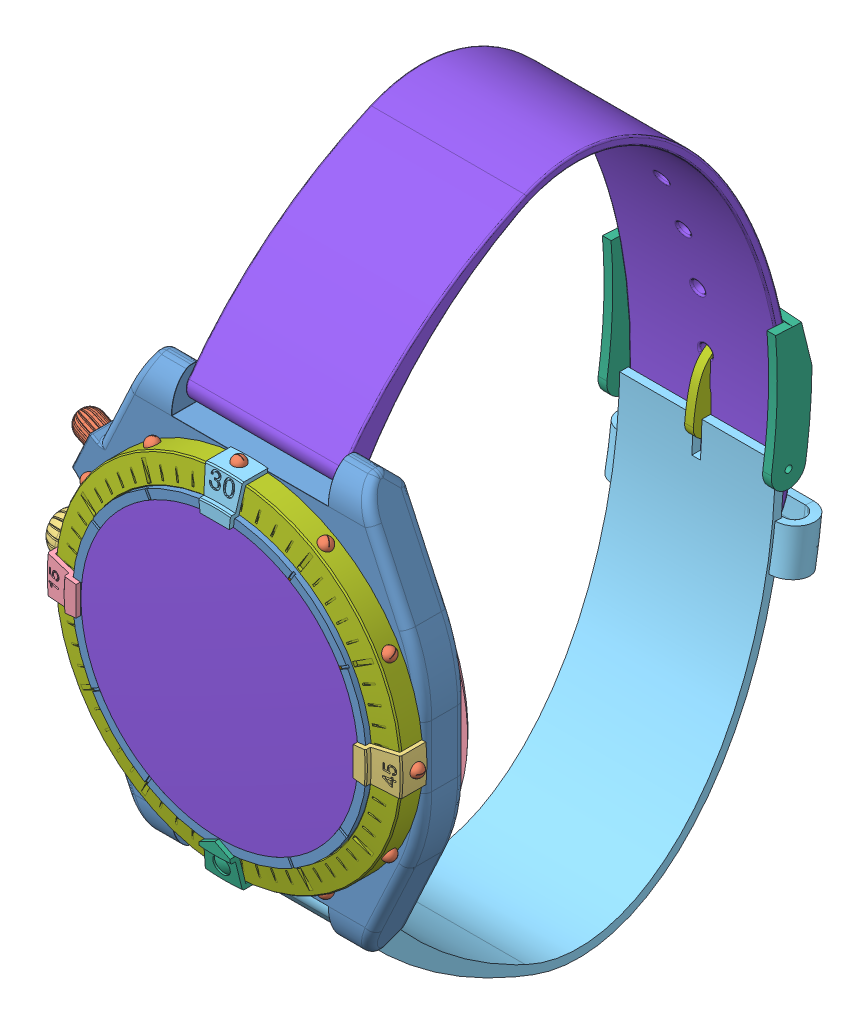
SolidWorks assembly Montre_Breitling-V0[1], configuration Default. Lengths in mm.
Overall size (46.88 84.89 60.5).
46 component instances, 26 part files, 4 mates.
Components (placement in the parent):
- Ensemble Bo_X2_00EE_X0_tier-1: Ensemble Bo_X2_00EE_X0_tier [Default] at origin size (46.19 48.49 11.5)
  - Bo_X2_00EE_X0_tier-1: Bo_X2_00EE_X0_tier [Default] at (6.9944 6.2325 -0.5535) x (1 0 0) z (0 -1 0) size (41 8.78 48.49)
  - Bouton Secondaire-1: Bouton Secondaire [Default] at (-13.9312 -5.698 1.9465) x (0.041442 -0.088873 0.99518) z (-0.906308 -0.422618 0) size (3.58 3.62 13.38)
  - Bouton Principal-1: Bouton Principal [Default] at (-15.5056 6.2325 1.9465) x (0 0 1) z (-1 0 0) size (5.93 5.96 12.38)
  - Bouton Secondaire-2: Bouton Secondaire [Default] at (-13.9312 18.163 1.9465) x (-0.041442 -0.088873 0.99518) z (-0.906308 0.422618 0) size (3.58 3.62 13.38)
  - Couvercle-1: Couvercle [Default] at (6.9944 6.2325 -0.5535) x (0.033164 0.99945 0) z (0 0 -1) size (40.29 40.29 4)
- Ensemble Bracelet-1: Ensemble Bracelet [Default] at origin size (22.65 84.89 56.01)
  - Bracelet Boucle-1: Bracelet Boucle [Default] at (7.0335 5.3195 -0.211) x (1 0 0) z (0 -0.99995 0.010001) size (22.65 54.44 43.47)
  - Boucle-1: Boucle [Default] at (-1.9665 12.8629 -0.8888) x (-1 0 0) z (0 0.998577 -0.05333) size (20 5.23 17)
  - Patte Boucle-1: Patte Boucle [Default] at (7.5335 13.0394 -0.9212) x (0 -0.057095 -0.998369) z (0 0.998369 -0.057095) size (5.72 1 11.64)
  - Bracelet Partie sans attaches-1: Bracelet Partie sans attaches [Default] at (7.0335 7.2551 -1.2657) x (-1 0 0) z (0 0.998192 0.060103) size (18.14 52.56 58.9)
- Ensemble Interieur Cadran-1: Ensemble Interieur Cadran [Default] at origin size (32.27 32.27 2.88)
  - Interieur Cadran-1: Interieur Cadran [Default] at (6.9944 6.2325 6.4465) x (-0.999964 -0.008468 0) z (0 0 1) size (32 32 1.1)
  - Aiguille Heures-1: Aiguille Heures [Default] at (6.9944 6.2325 7.6965) x (0 0 1) z (0.872293 -0.488983 0) size (0.05 1.25 8.61)
  - Aiguille Minutes-1: Aiguille Minutes [Default] at (6.9944 6.2325 7.5465) x (0 0 1) z (-0.877891 -0.47886 0) size (0.05 1.5 12.74)
  - Aiguille Secondes-1: Aiguille Secondes [Default] at (6.9944 6.2325 7.7465) x (0 0 1) z (0 -1 0) size (0.05 2.24 15.03)
  - Cadran Chrono Minutes-1: Cadran Chrono Minutes [Default] at (7.0685 -2.5172 7.3465) x (0 0 1) z (-0.019677 -0.999806 0) size (0.11 7 7)
  - Cadran Chrono Heures-1: Cadran Chrono Heures [Default] at (6.9203 14.9822 7.3465) x (0 0 1) z (-0.002344 -0.999997 0) size (0.1 7 7)
  - Cadran Chrono Secondes-1: Cadran Chrono Secondes [Default] at (15.7441 6.3066 7.3465) x (0 0 1) z (-0.022282 -0.999752 0) size (0.2 7 7)
  - Aiguille Cadran Annexe-1: Aiguille Cadran Annexe [Default] at (7.0685 -2.5172 7.5465) x (0 0 -1) z (-0.01715 -0.999853 0) size (0.1 0.6 3.48)
  - Aiguille Cadran Annexe-2: Aiguille Cadran Annexe [Default] at (6.9203 14.9822 7.5465) x (0 0 -1) z (-0.010944 -0.99994 0) size (0.1 0.6 3.48)
  - Aiguille Cadran Annexe-3: Aiguille Cadran Annexe [Default] at (15.7441 6.3066 7.5465) x (0 0 -1) z (-0.020458 -0.999791 0) size (0.1 0.6 3.48)
  - Disque Date-1: Disque Date [Default] at (6.9944 6.2325 6.6465) x (0 0 1) z (-0.007629 -0.999971 0) size (0.2 24 24)
  - Axe principal-1: Axe principal [Default] at (6.9944 6.2325 5.3793) size (0.48 0.47 2.57)
  - Axe secondaire-1: Axe secondaire [Default] at (15.7441 6.3066 5.0808) size (0.27 0.27 2.54)
  - Axe secondaire-2: Axe secondaire [Default] at (6.9203 14.9822 5.0772) size (0.27 0.27 2.54)
  - Axe secondaire-3: Axe secondaire [Default] at (7.0685 -2.5172 5.0863) size (0.27 0.27 2.54)
- Cadran Ensemble Tournant-1: Cadran Ensemble Tournant [Default] at (0 5.679 -0.5535) x (1 0 0) z (0 -1 0) size (43.02 4.2 43.01)
  - Vis Cadran-1: Vis Cadran [Default] at (16.9898 6.25 16.7589) x (0.75 -0.5 -0.433013) z (-0.433013 -0.866025 0.25) size (1.79 4.27 1.74)
  - Vis Cadran-2: Vis Cadran [Default] at (24.2921 6.25 9.4333) x (0.25 -0.866025 -0.433013) z (-0.433013 -0.5 0.75) size (1.79 4.27 1.74)
  - Vis Cadran-3: Vis Cadran [Default] at (27.4788 6.25 -0.5535) x (0 -1 0) z (0 0 1) size (1.79 4.27 1.74)
  - Vis Cadran-4: Vis Cadran [Default] at (24.3008 6.25 -10.5454) x (-0.25 -0.866025 -0.433013) z (0.433013 -0.5 0.75) size (1.79 4.27 1.74)
  - Vis Cadran-5: Vis Cadran [Default] at (16.9876 6.25 -17.8622) x (-0.75 -0.5 -0.433013) z (0.433013 -0.866025 0.25) size (1.79 4.27 1.74)
  - Vis Cadran-6: Vis Cadran [Default] at (6.9944 6.25 -21.0274) x (-1 0 0) z (0 -1 0) size (1.79 4.27 1.74)
  - Vis Cadran-7: Vis Cadran [Default] at (-2.9952 6.25 -17.856) x (-0.75 0.5 0.433013) z (-0.433013 -0.866025 0.25) size (1.79 4.27 1.74)
  - Vis Cadran-8: Vis Cadran [Default] at (-10.3261 6.25 -10.5536) x (-0.25 0.866025 0.433013) z (-0.433013 -0.5 0.75) size (1.79 4.27 1.74)
  - Vis Cadran-9: Vis Cadran [Default] at (-13.5085 6.25 -0.5535) x (0 1 0) z (0 0 1) size (1.79 4.27 1.74)
  - Vis Cadran-10: Vis Cadran [Default] at (-10.3183 6.25 9.442) x (0.25 0.866025 0.433013) z (0.433013 -0.5 0.75) size (1.79 4.27 1.74)
  - Vis Cadran-11: Vis Cadran [Default] at (-3.0016 6.25 16.76) x (0.866024 -0.001554 0.499999) z (-0.001346 -0.999999 -0.000777) size (1.79 4.27 1.74)
  - Vis Cadran-12: Vis Cadran [Default] at (6.9944 6.25 19.9518) x (1 0 0) z (0 -1 0) size (1.79 4.27 1.74)
  - Index Ouest-1: Index Ouest [Default] at (6.9944 5.0627 -0.5535) x (0 0 1) z (0 1 0) size (4.29 4.5 4)
  - Index Est-1: Index Est [Default] at (6.9944 5.0627 -0.5535) x (0 0 -1) z (0 1 0) size (4.29 4.5 4)
  - Index Sud-1: Index Sud [Default] at (6.9944 5.0627 -0.5535) x (1 0 0) z (0 1 0) size (4.29 4.5 4)
  - Index Nord-1: Index Nord [Default] at (6.9947 5.0627 -0.5414) x (-1 -0.000228 0) z (-0.000228 1 0) size (4.29 4.5 4)
  - Cadran Or-1: Cadran Or [Default] at (6.9944 5 -0.5535) size (40 2.98 40)
- Glass-1: Glass [Default] at (6.9944 6.2325 7.4465) x (-0.999964 -0.008468 0) z (0 0 1) size (32 32 0.32)
Mates (geometry in assembly coordinates):
- InPlace1: in place: plane of Ensemble Interieur Cadran-1/Interieur Cadran-1 through (7.1299 -9.7669 7.4465) normal (0 0 1); plane of ? through (0 0 7.4465) normal (0 0 1); moOrthogonalPlaneRef_w of Ensemble Interieur Cadran-1/Interieur Cadran-1 through (7.1299 -9.7669 7.4465) normal (0 0 1); plane of ? through (0 0 7.4465) normal (0 1 0); plane of Ensemble Interieur Cadran-1/Interieur Cadran-1 through (7.1299 -9.7669 7.4465) normal (0 0 1); plane of ? through (0 0 7.4465) normal (1 0 0); plane of Ensemble Interieur Cadran-1/Interieur Cadran-1 through (7.1299 -9.7669 7.4465) normal (0 0 1); unknown of Glass-1
- Coincident1: coincident aligned: plane of Ensemble Interieur Cadran-1/Interieur Cadran-1; plane of Glass-1
- Coincident2: coincident aligned: moOrthogonalPlaneRef_w of Ensemble Interieur Cadran-1/Interieur Cadran-1 through (6.9944 6.2325 7.4465) normal (0.008468 -0.999964 0); plane of Glass-1
- Coincident3: coincident anti-aligned: moOrthogonalPlaneRef_w of Ensemble Interieur Cadran-1/Interieur Cadran-1 through (6.9944 6.2325 7.4465) normal (0.999964 0.008468 0); plane of Glass-1
